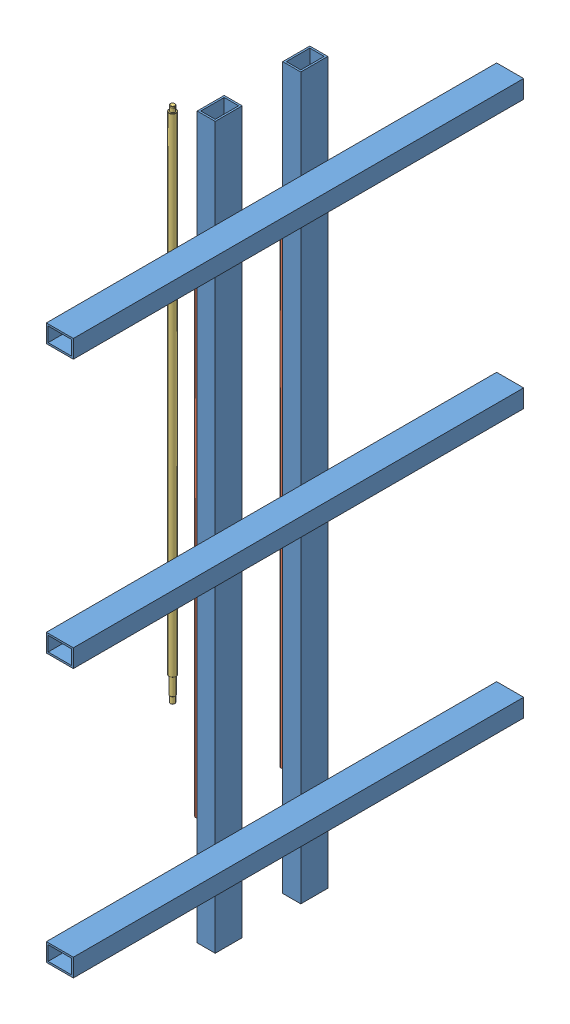
SolidWorks assembly Основание, configuration По умолчанию. Lengths in mm.
Overall size (294.07 1600 1000).
8 component instances, 3 part files, 8 mates.
Components (placement in the parent):
- Труба стальная 60х40х4-1: Труба стальная 60х40х4 [1000] at (-49.6739 3.0422 46.6321) size (60 40 1000)
- Труба стальная 60х40х4-2: Труба стальная 60х40х4 [1600] at (-99.6739 -576.9578 141.6321) x (0 0 1) z (0 -1 0) size (60 40 1600)
- Труба стальная 60х40х4-3: Труба стальная 60х40х4 [1000] at (-49.6739 -591.9578 46.6321) size (60 40 1000)
- Труба стальная 60х40х4-4: Труба стальная 60х40х4 [1000] at (-49.6739 -1186.9578 46.6321) size (60 40 1000)
- Труба стальная 60х40х4-5: Труба стальная 60х40х4 [1600] at (-99.6739 -576.9578 -48.3679) x (0 0 1) z (0 -1 0) size (60 40 1600)
- SBR16-1: SBR16 [L1100] at (-144.6739 -610.218 141.6321) x (0 1 0) z (0 0 1) size (1100 33 40)
- Винт ШВП RM1605-1: Винт ШВП RM1605 [L1150] at (-305.7453 -1073.604 40.092) size (16 1150 16)
- SBR16-2: SBR16 [L1100] at (-144.6739 -610.218 -48.3679) x (0 1 0) z (0 0 1) size (1100 33 40)
Mates (geometry in assembly coordinates):
- Совпадение1: coincident anti-aligned: plane of Труба стальная 60х40х4-1 through (-79.6739 -16.9578 -453.3679) normal (-1 0 0); plane of Труба стальная 60х40х4-2 through (-79.6739 223.0422 111.6321) normal (1 0 0)
- Расстояние1: distance = 125 mm aligned: plane of Труба стальная 60х40х4-2 through (-79.6739 223.0422 171.6321) normal (0 0 1); plane of Труба стальная 60х40х4-1 through (-49.6739 3.0422 46.6321) normal (0 0 1)
- Расстояние2: distance = 200 mm aligned: plane of Труба стальная 60х40х4-1 through (-79.6739 23.0422 -453.3679) normal (0 1 0); plane of Труба стальная 60х40х4-2 through (-99.6739 223.0422 141.6321) normal (0 1 0)
- Совпадение3: coincident aligned: plane of Труба стальная 60х40х4-2 through (-119.6739 223.0422 111.6321) normal (-1 0 0); plane of Труба стальная 60х40х4-5 through (-119.6739 223.0422 -78.3679) normal (-1 0 0)
- Совпадение4: coincident aligned: plane of Труба стальная 60х40х4-2 through (-99.6739 223.0422 141.6321) normal (0 1 0); plane of Труба стальная 60х40х4-5 through (-99.6739 223.0422 -48.3679) normal (0 1 0)
- Расстояние4: distance = 125 mm anti-aligned: plane of Труба стальная 60х40х4-5 through (-79.6739 223.0422 -78.3679) normal (0 0 -1); plane of Труба стальная 60х40х4-1 through (-49.6739 3.0422 46.6321) normal (0 0 1)
- Совпадение7: coincident anti-aligned: plane of Труба стальная 60х40х4-2 through (-119.6739 223.0422 111.6321) normal (-1 0 0); plane of SBR16-1 through (-119.6739 -60.218 141.6321) normal (1 0 0)
- Совпадение8: coincident aligned: plane of Труба стальная 60х40х4-2; plane of SBR16-1 through (-144.6739 -610.218 141.6321) normal (0 0 1)
